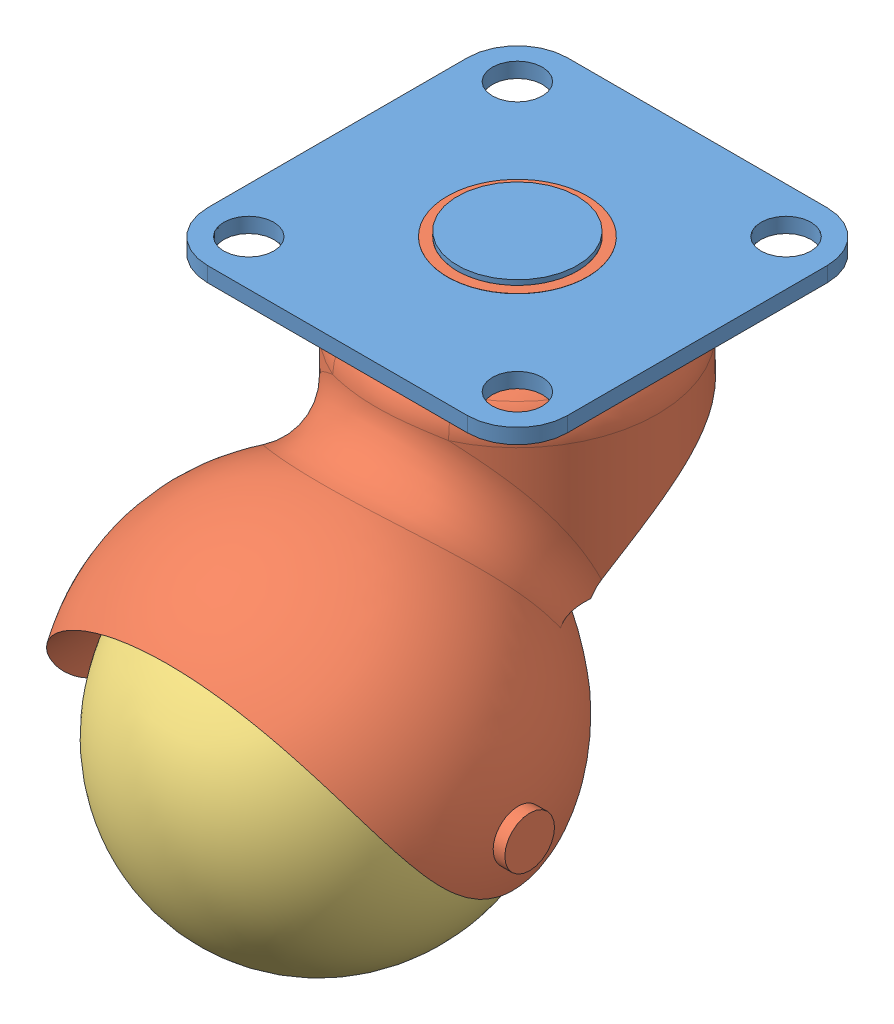
SolidWorks assembly Assem1, configuration Default. Lengths in mm.
Overall size (42.28 50.44 56.08).
3 component instances, 3 part files, 2 mates.
Components (placement in the parent):
- roller 1-1: roller 1 [Default] at (12.6358 25.0362 25.8487) size (36 10 36)
- roller 2-1: roller 2 [Default] at (12.6358 14.5506 25.8487) x (0.999985 0 -0.005501) z (0.005501 0 0.999985) size (42 38.11 50.51)
- roller 3-1: roller 3 [Default] at (13.5515 -5.4005 45.8439) x (0.999985 0 -0.005501) z (0.005501 0 0.999985) size (32.2 36 36)
Mates (geometry in assembly coordinates):
- Concentric2: concentric anti-aligned: circle of roller 1-1; circle of roller 2-1
- Concentric1: concentric anti-aligned: circle of roller 2-1; circle of roller 3-1
